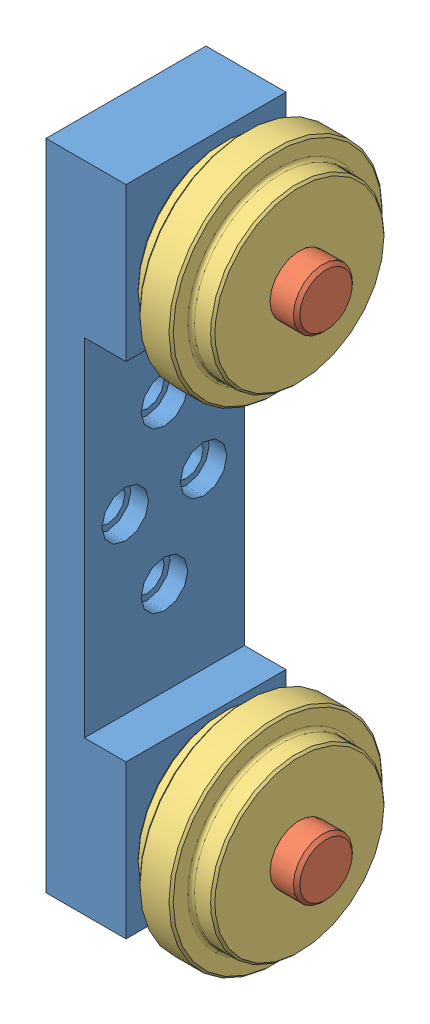
SolidWorks assembly 2759-1, configuration Default. Lengths in mm.
Overall size (47.62 168.28 50.8).
7 component instances, 4 part files, 0 mates.
Components (placement in the parent):
- 2757-1_b-1: 2757-1_b [Default] at (9.144 0 0) x (0 0 -1) z (1 0 0) size (38.1 155.57 19.05)
- 2290_b-1: 2290_b [Default] at (41.3004 58.7375 0) x (-1 0 0) z (0 0 1) size (38.1 14.02 14.02)
- 2290_w-1: 2290_w [Default] at (32.1564 58.7375 0) size (18.29 50.8 50.8)
- 2290_p2-1: 2290_p2 [Default] at (20.6375 58.7375 0) size (3.17 19.05 19.05)
- 2290_b-2: 2290_b [Default] at (41.3004 -58.7375 0) x (-1 0 0) z (0 0 1) size (38.1 14.02 14.02)
- 2290_w-2: 2290_w [Default] at (32.1564 -58.7375 0) size (18.29 50.8 50.8)
- 2290_p2-2: 2290_p2 [Default] at (20.6375 -58.7375 0) size (3.17 19.05 19.05)
